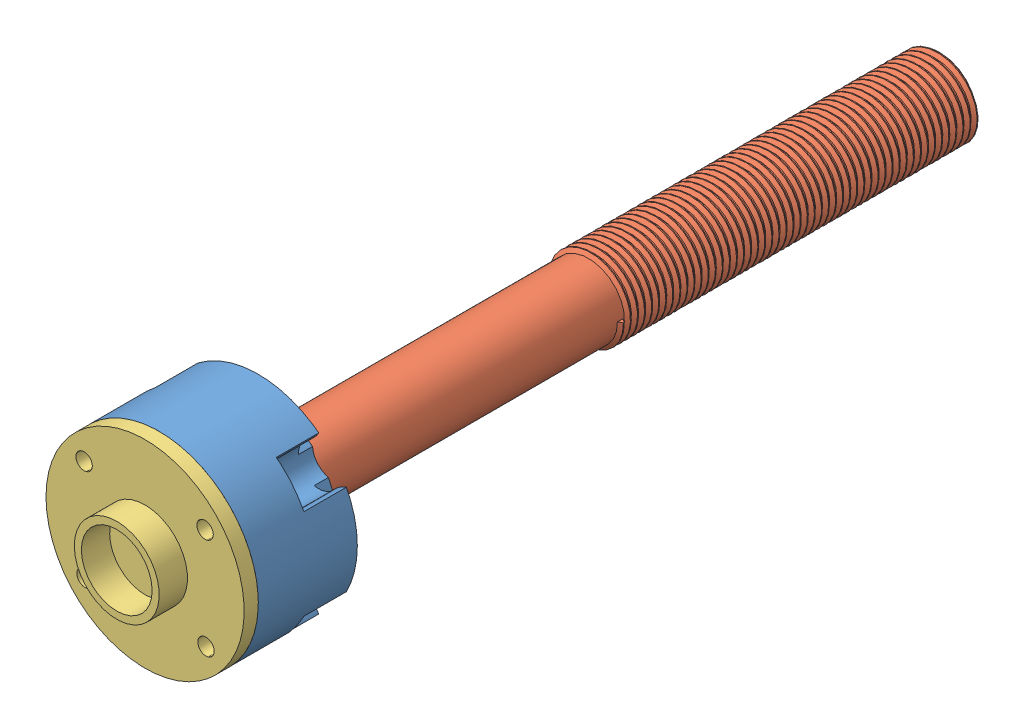
SolidWorks assembly Steering thor joint, configuration Default. Lengths in mm.
Overall size (14.13 14.13 58.56).
3 component instances, 3 part files, 4 mates.
Components (placement in the parent):
- bolt head-1: bolt head [Default] at (-18.4031 26.2188 19.7392) size (14 14 8)
- Bogie bolt-1: Bogie bolt [Default] at (-18.4064 26.2246 14.7392) x (-1 0 0) z (0 0 -1) size (9 10.39 55.56)
- Bolt servo connector-1: Bolt servo connector [Default] at (-18.4031 26.2188 19.7392) x (0.99996 0.008969 0) z (0 0 1) size (14 14 3)
Mates (geometry in assembly coordinates):
- Coincident14: coincident: plane of bolt head-1 through (-18.4031 26.2188 19.7392) normal (0 0 1); plane of Bogie bolt-1 through (-18.4064 26.2246 19.7392) normal (0 0 1)
- Coincident16: coincident: line of bolt head-1 through (-15.0425 29.4786 19.7392) axis (-0.866025 0.5 0); line of Bogie bolt-1 through (-18.4064 31.4207 19.7392) axis (0.866025 -0.5 0)
- Coincident18: coincident: plane of bolt head-1 through (-22.9064 26.2188 14.7392) normal (1 0 0); plane of Bogie bolt-1 through (-22.9064 23.6265 19.7392) normal (-1 0 0)
- Coincident19: coincident: circle of bolt head-1; circle of Bolt servo connector-1
